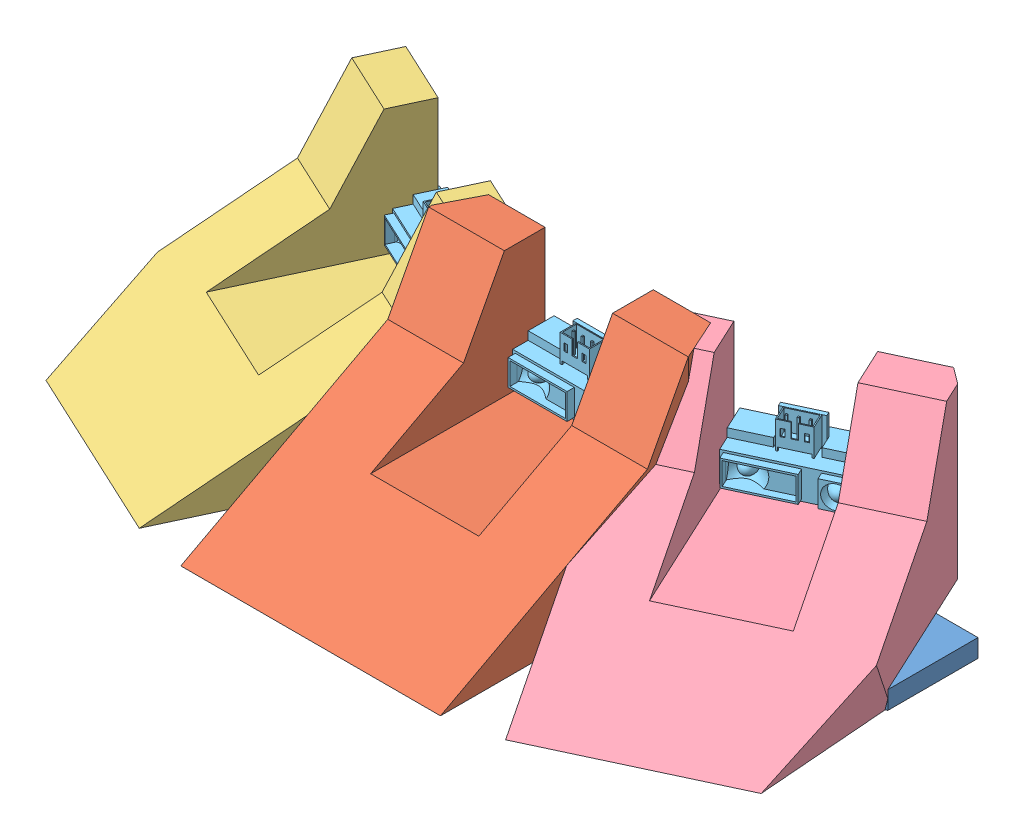
SolidWorks assembly Ensamble_Frente_2.0, configuration Predeterminado. Lengths in mm.
Overall size (214.58 51.82 94.1).
7 component instances, 5 part files, 22 mates.
Components (placement in the parent):
- Base_Frente2.0-1: Base_Frente2.0 [Predeterminado] at (127.778 25.9089 191.8027) x (-1 0 0) z (0 0 -1) size (193.45 5 53.32)
- Frente_Centro_Acero-1: Frente_Centro_Acero [Predeterminado] at (163.778 25.9089 146.8027) x (-1 0 0) z (0 0 -1) size (72 51.82 70)
- Frente_LateralIzq_Aceros-1: Frente_LateralIzq_Aceros [Predeterminado] at (50.0732 25.9089 122.7034) x (-0.422618 0 0.906308) z (-0.906308 0 -0.422618) size (70 51.82 67)
- Frente_LateralDerecho_Acero-1: Frente_LateralDerecho_Acero [Predeterminado] at (144.7602 25.9089 151.0188) x (0.422618 0 0.906308) z (-0.906308 0 0.422618) size (70 51.82 67)
- Sharp-1: Sharp [Default] at (81.0532 49.2289 134.9428) x (-0.906308 0 -0.422618) z (-0.422618 0 0.906308) size (44.5 18.9 13.5)
- Sharp-2: Sharp [Default] at (128.028 49.2289 144.8027) x (-1 0 0) z (0 0 1) size (44.5 18.9 13.5)
- Sharp-3: Sharp [Default] at (174.5028 49.2289 134.9428) x (-0.906308 0 0.422618) z (0.422618 0 0.906308) size (44.5 18.9 13.5)
Mates (geometry in assembly coordinates):
- Coincidente1: coincident: plane of Base_Frente2.0-1 through (91.778 30.9089 191.8027) normal (0 0 1); plane of Frente_Centro_Acero-1 through (163.779 25.9089 191.8027) normal (0 0 -1)
- Coincidente2: coincident: plane of Base_Frente2.0-1 through (127.778 30.9089 191.8027) normal (0 1 0); plane of Frente_Centro_Acero-1 through (163.779 30.9089 146.8027) normal (0 -1 0)
- Coincidente3: coincident: line of Base_Frente2.0-1 through (163.778 30.9089 191.8027) axis (0 -1 0); line of Frente_Centro_Acero-1 through (163.778 25.9089 191.8027) axis (0 1 0)
- Paralelo1: parallel: plane of Base_Frente2.0-1 through (91.778 30.9089 191.8027) normal (-0.422618 0 0.906308); plane of Frente_LateralIzq_Aceros-1 through (91.7789 25.9089 191.8031) normal (0.422618 0 -0.906308)
- Coincidente5: coincident: plane of Base_Frente2.0-1 through (127.778 30.9089 191.8027) normal (0 1 0); plane of Frente_LateralIzq_Aceros-1 through (110.7967 30.9089 151.0192) normal (0 -1 0)
- Coincidente6: coincident: plane of Base_Frente2.0-1 through (91.778 30.9089 191.8027) normal (-0.422618 0 0.906308); plane of Frente_LateralIzq_Aceros-1 through (91.7789 25.9089 191.8031) normal (0.422618 0 -0.906308)
- Paralelo3: parallel: plane of Base_Frente2.0-1 through (163.778 30.9089 191.8027) normal (0.422618 0 0.906308); plane of Frente_LateralDerecho_Acero-1 through (224.5015 25.9089 163.4868) normal (-0.422618 0 -0.906308)
- Coincidente12: coincident: plane of Base_Frente2.0-1 through (127.778 30.9089 191.8027) normal (0 1 0); plane of Frente_LateralDerecho_Acero-1 through (205.4837 30.9089 122.703) normal (0 -1 0)
- Coincidente13: coincident: plane of Base_Frente2.0-1 through (163.778 30.9089 191.8027) normal (0.422618 0 0.906308); plane of Frente_LateralDerecho_Acero-1 through (224.5015 25.9089 163.4868) normal (-0.422618 0 -0.906308)
- Coincidente14: coincident: line of Base_Frente2.0-1 through (224.5006 30.9089 163.4872) axis (0 -1 0); line of Frente_LateralDerecho_Acero-1 through (224.5006 30.9089 163.4872) axis (0 -1 0)
- Paralelo4: parallel: plane of Frente_LateralIzq_Aceros-1 through (50.0732 25.9089 122.7034) normal (0.422618 0 -0.906308); plane of Sharp-1 through (97.8199 49.2289 142.7613) normal (0.422618 0 -0.906308)
- Coincidente17: coincident: plane of Frente_LateralIzq_Aceros-1 through (66.8399 42.7289 130.5218) normal (0.906308 0 0.422618); plane of Sharp-1 through (61.9798 55.7289 140.9444) normal (-0.906308 0 -0.422618)
- Coincidente18: coincident: plane of Frente_LateralIzq_Aceros-1 through (50.0732 25.9089 122.7034) normal (0.422618 0 -0.906308); plane of Sharp-1 through (63.4412 49.2289 128.937) normal (-0.422618 0 0.906308)
- Paralelo5: parallel: plane of Frente_Centro_Acero-1 through (91.778 25.9089 146.8027) normal (0 0 -1); plane of Sharp-2 through (146.528 49.2289 144.8027) normal (0 0 -1)
- Coincidente21: coincident: plane of Frente_Centro_Acero-1 through (142.778 42.7289 146.8027) normal (-1 0 0); plane of Sharp-2 through (142.778 55.7289 158.3027) normal (1 0 0)
- Coincidente23: coincident: plane of Frente_Centro_Acero-1 through (91.778 25.9089 146.8027) normal (0 0 -1); plane of Sharp-2 through (109.528 49.2289 146.8027) normal (0 0 1)
- Paralelo6: parallel: plane of Frente_LateralDerecho_Acero-1 through (144.7602 25.9089 151.0188) normal (-0.422618 0 -0.906308); plane of Sharp-3 through (191.2695 49.2289 127.1244) normal (-0.422618 0 -0.906308)
- Coincidente26: coincident: plane of Frente_LateralDerecho_Acero-1 through (188.7161 42.7289 130.5218) normal (-0.906308 0 0.422618); plane of Sharp-3 through (193.5762 55.7289 140.9444) normal (0.906308 0 -0.422618)
- Coincidente27: coincident: plane of Frente_LateralDerecho_Acero-1 through (144.7602 25.9089 151.0188) normal (-0.422618 0 -0.906308); plane of Sharp-3 through (192.1148 49.2289 128.937) normal (0.422618 0 0.906308)
- Coincidente28: coincident: plane of Frente_LateralIzq_Aceros-1 through (50.0732 42.7289 122.7034) normal (0 1 0); plane of Sharp-1 through (88.7159 42.7289 153.4116) normal (0 -1 0)
- Coincidente29: coincident: plane of Frente_Centro_Acero-1 through (163.778 42.7289 146.8027) normal (0 1 0); plane of Sharp-2 through (142.778 42.7289 158.3027) normal (0 -1 0)
- Coincidente30: coincident: plane of Frente_LateralDerecho_Acero-1 through (144.7602 42.7289 151.0188) normal (0 1 0); plane of Sharp-3 through (193.5762 42.7289 140.9444) normal (0 -1 0)
